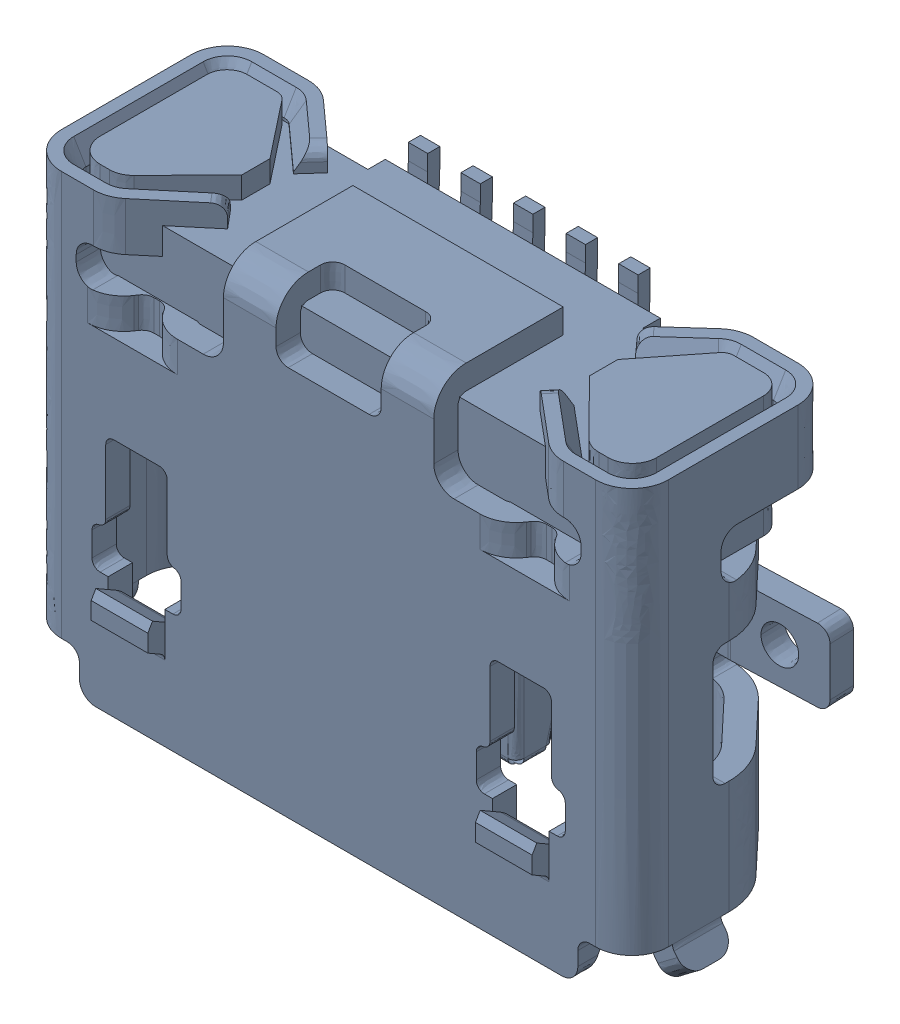
SolidWorks assembly J7, configuration Default. Lengths in mm.
Overall size (7.92 5.67 3.01).
4 component instances, 3 part files, 0 mates.
Components (placement in the parent):
- Amphenol 10118192-1: Amphenol 10118192 [Default] at (-97.9992 -12.7205 -0.35) x (1 0 0) z (0 -1 0) size (7.92 3.01 5.67)
  - unnamed-1: unnamed [Default] at origin size (6.89 2.28 4.27)
  - unnamed-1-1: unnamed-1 [Default] at origin size (0 0.01 0)
  - unnamed-2-1: unnamed-2 [Default] at origin size (7.92 3.01 5.67)
